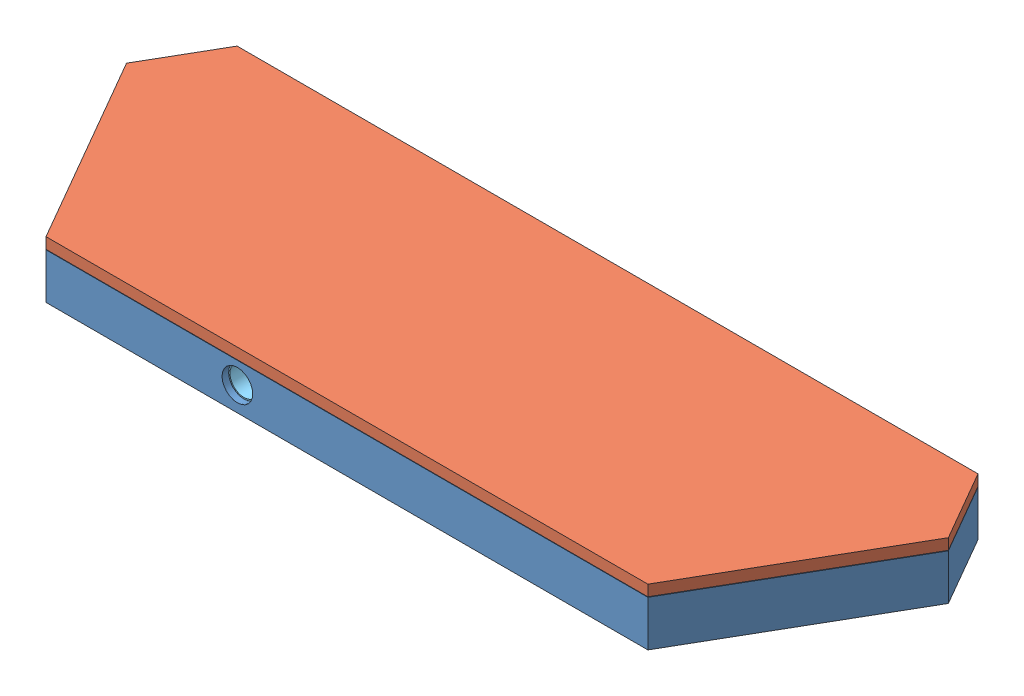
SolidWorks assembly smartleaf_controller, configuration Défaut. Lengths in mm.
Overall size (204.69 13 192.13).
6 component instances, 6 part files, 16 mates.
Components (placement in the parent):
- smartleaf_controller_bottom-1: smartleaf_controller_bottom [Défaut] x (0.5 0 -0.866025) z (0.866025 0 0.5) size (128.1 12 162.4)
- smartleaf_controller_top-1: smartleaf_controller_top [Défaut] at (0 13 0) x (1 0 0) z (0 -1 0) size (187.52 59.47 4.8)
- ESP32_Mini_full-1: ESP32_Mini_full [Défaut] at (28 5.1 -36.8171) x (0 0 1) z (-1 0 0) size (31.2 3.67 39)
- 610006243021-1: 610006243021 [Défaut] at (0 6.5 -42.7626) x (0 1 0) z (0 0 -1) size (7.62 7.21 3.7)
- 61300625721-1: 61300625721 [Défaut] at (0 6.5 -43.5034) x (0 -1 0) z (0 0 -1) size (8.22 5.33 8.1) (hidden)
- 694106301002-1: 694106301002 [Default] at (-23.85 5.5 -5) x (0 1 0) z (-1 0 0) size (9.5 14.5 14.5)
Mates (geometry in assembly coordinates):
- Coïncidente8: coincident: plane of smartleaf_controller_bottom-1 through (0 0 0) normal (1 0 0); plane of assembly through (0 0 0) normal (1 0 0)
- Coïncidente9: coincident: plane of smartleaf_controller_bottom-1 through (0 0 0) normal (0 1 0); plane of assembly through (0 0 0) normal (0 1 0)
- Coïncidente10: coincident: plane of smartleaf_controller_bottom-1 through (68.6667 0 0) normal (0 0 1); plane of assembly through (0 0 0) normal (0 0 1)
- Coïncidente16: coincident: plane of smartleaf_controller_bottom-1 through (0 0 0) normal (1 0 0); plane of 610006243021-1 through (0 6.5 -42.7626) normal (1 0 0)
- Coïncidente17: coincident: plane of smartleaf_controller_bottom-1 through (0 6.5 0) normal (0 1 0); plane of 610006243021-1 through (0 6.5 -42.7626) normal (0 1 0)
- Coïncidente18: coincident: plane of smartleaf_controller_bottom-1 through (0 0 0) normal (1 0 0); plane of 61300625721-1 through (0 6.5 -43.5034) normal (-1 0 0)
- Coïncidente19: coincident: plane of smartleaf_controller_bottom-1 through (0 6.5 0) normal (0 1 0); plane of 61300625721-1 through (0 6.5 -43.5034) normal (0 -1 0)
- Coïncidente20: coincident: plane of smartleaf_controller_top-1 through (0 13 0) normal (1 0 0); plane of assembly through (0 0 0) normal (1 0 0)
- Coïncidente21: coincident: plane of smartleaf_controller_top-1 through (0 13 0) normal (0 0 1); plane of assembly through (0 0 0) normal (0 0 1)
- Coïncidente22: coincident: plane of smartleaf_controller_bottom-1 through (0 12 0) normal (0 1 0); plane of smartleaf_controller_top-1 through (0 12 0) normal (0 -1 0)
- Parallèle3: parallel: plane of smartleaf_controller_bottom-1 through (-72.6891 1 -41.9671) normal (0 1 0); plane of 694106301002-1 through (-18.5 1 -1.5) normal (0 -1 0)
- Coïncidente24: coincident: plane of smartleaf_controller_bottom-1 through (0 0 -1.5) normal (0 0 -1); plane of 694106301002-1 through (-23.85 5.5 -1.5) normal (0 0 1)
- Coaxiale3: concentric: cylinder of smartleaf_controller_bottom-1 through (-25 5.5 -10) axis (0 0 1) radius 3.5; cylinder of 694106301002-1 through (-25 5.5 -14.6) axis (0 0 1) radius 1
- Coïncidente25: coincident: plane of smartleaf_controller_bottom-1 through (0 5.1 0) normal (0 1 0); plane of ESP32_Mini_full-1 through (14 5.1 -50.9171) normal (0 -1 0)
- Distance1: distance = 0.5 mm: plane of ESP32_Mini_full-1 through (47.5 6.1 -50.4171) normal (1 0 0); plane of smartleaf_controller_bottom-1 through (48 6.6 -41.9671) normal (-1 0 0)
- Coïncidente26: coincident: plane of smartleaf_controller_bottom-1 through (23.5 6.6 -21.2171) normal (0 0 -1); plane of ESP32_Mini_full-1 through (45.5 6.1 -21.2171) normal (0 0 1)
